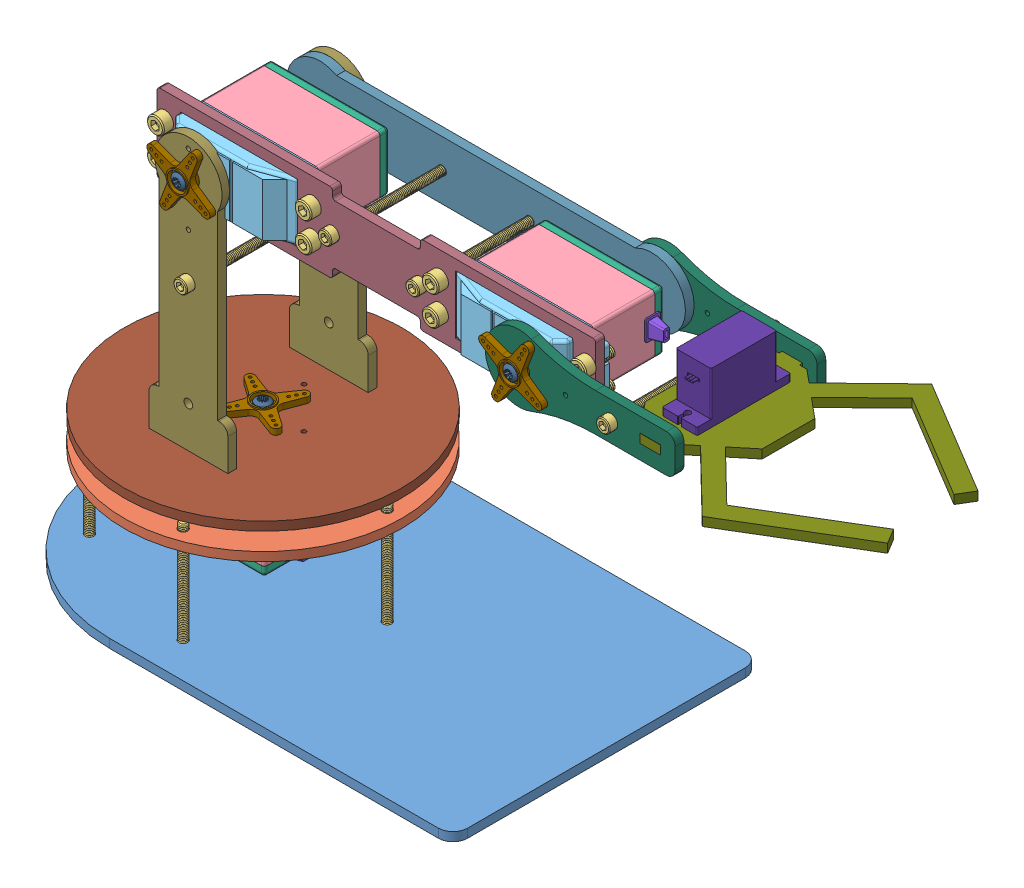
SolidWorks assembly robot_esamble_links, configuration Predeterminado. Lengths in mm.
Overall size (282.35 247.5 137.24).
60 component instances, 17 part files, 12 mates.
Components (placement in the parent):
- base_link_littleRobot-1: base_link_littleRobot [Predeterminado] at origin size (170 50.72 105)
  - A_pieza_arm_robot_v0-1: A_pieza_arm_robot_v0 [Predeterminado] x (0 0 -1) z (0 1 0) size (105 170 3)
  - B_pieza_arm_robot_v0-1: B_pieza_arm_robot_v0 [Predeterminado] at (0 33 0) x (-1 0 0) z (0 1 0) size (95 95 3)
  - socket head cap screw_ai-1: socket head cap screw_ai [HX-SHCS 0.112-48x1.5x1.5-S] at (13.1332 -2.8448 -40.4199) x (0 1 0) z (0 0 1) size (40.94 4.65 4.65)
  - socket head cap screw_ai-2: socket head cap screw_ai [HX-SHCS 0.112-48x1.5x1.5-S] at (-34.3832 -2.8448 -24.9809) x (0 1 0) z (0 0 1) size (40.94 4.65 4.65)
  - socket head cap screw_ai-3: socket head cap screw_ai [HX-SHCS 0.112-48x1.5x1.5-S] at (-34.3832 -2.8448 24.9809) x (0 1 0) z (0 0 1) size (40.94 4.65 4.65)
  - socket head cap screw_ai-4: socket head cap screw_ai [HX-SHCS 0.112-48x1.5x1.5-S] at (13.1332 -2.8448 40.4199) x (0 1 0) z (0 0 1) size (40.94 4.65 4.65)
  - socket head cap screw_ai-5: socket head cap screw_ai [HX-SHCS 0.112-48x1.5x1.5-S] at (42.5 -2.8448 0) x (0 1 0) z (0 0 1) size (40.94 4.65 4.65)
  - Servomoteur Futuba S3003-4: Servomoteur Futuba S3003 [Défaut] at (-9.3643 24.2642 -40.4) size (55.5 42.98 32.41)
    - Boitier-1: Boitier [Défaut] at (8.3252 -16.2642 40.4) size (40.4 21 20)
    - Couvercle supérieure-1: Couvercle supérieure [Défaut] at (9.3643 6.7358 40.4) size (55.5 13 20)
    - Couvercle inférieure-1: Couvercle inférieure [Défaut] at (4.9957 -19.3642 40.4) size (40.4 3.1 20)
    - Axe-1: Axe [Défaut] at (9.3643 15.2358 40.4) size (5 16 5)
    - Passe fil-1: Passe fil [Défaut] at (17.8143 -15.2642 40.4) x (0 0 -1) z (1 0 0) size (7 5 7.5)
    - Palonnier-1: Palonnier [Défaut] at (9.3643 21.7358 40.4) x (0.465117 0 -0.885249) z (0 1 0) size (24 24 5)
    - Vis CBL Z, M 2.5 - 5-1: Vis CBL Z, M 2.5 - 5 [Défaut] at (9.3643 21.7358 40.4) x (0.991239 0 0.132079) z (0 1 0) size (5 5 6.88)
  - socket head cap screw_ai-22: socket head cap screw_ai [HX-SHCS 0.138-40x0.3125x0.3125-S] at (15.5 39.5052 5) x (0 -1 0) z (0 0 1) size (11.44 5.74 5.74)
  - socket head cap screw_ai-23: socket head cap screw_ai [HX-SHCS 0.138-40x0.3125x0.3125-S] at (15.5 39.5052 -5) x (0 -1 0) z (0 0 1) size (11.44 5.74 5.74)
  - socket head cap screw_ai-24: socket head cap screw_ai [HX-SHCS 0.138-40x0.3125x0.3125-S] at (-35 39.5052 5) x (0 -1 0) z (0 0 1) size (11.44 5.74 5.74)
  - socket head cap screw_ai-25: socket head cap screw_ai [HX-SHCS 0.138-40x0.3125x0.3125-S] at (-35 39.5052 -5) x (0 -1 0) z (0 0 1) size (11.44 5.74 5.74)
- link_1_littleRobot-1: link_1_littleRobot [Predeterminado] at (0 42 0) size (95 96 95)
  - H_pieza_arm_robot_v0-1: H_pieza_arm_robot_v0 [Predeterminado] x (0 0 -1) z (0 1 0) size (95 95 3)
  - D_pieza_arm_robot_v0-1: D_pieza_arm_robot_v0 [piexa_motor_leva] at (0 84.5 25.5) x (-1 0 0) z (0 0 -1) size (27 96 3)
  - D_pieza_arm_robot_v0-2: D_pieza_arm_robot_v0 [Predeterminado] at (0 84.5 -22.5) x (-1 0 0) z (0 0 -1) size (27 96 3)
  - socket head cap screw_ai-6: socket head cap screw_ai [HX-SHCS 0.112-48x2.25x2.25-S] at (0 53 28.3448) x (0 0 -1) z (1 0 0) size (59.99 4.65 4.65)
- link_2_littleRobot-1: link_2_littleRobot [Predeterminado] at (-18.25 113 17.932) size (150.24 126.5 50.43)
  - C_pieza_arm_robot_v0-1: C_pieza_arm_robot_v0 [Predeterminado] at (75 13.5 -3) x (-1 0 0) z (0 0 1) size (150 27 3)
  - Servomoteur Futuba S3003-2: Servomoteur Futuba S3003 [Défaut] at (122.3857 53.9 -11.7358) x (1 0 0) z (0 -1 0) size (55.5 42.98 32.41)
    - Boitier-1: Boitier [Défaut] at (8.3252 -16.2642 40.4) size (40.4 21 20)
    - Couvercle supérieure-1: Couvercle supérieure [Défaut] at (9.3643 6.7358 40.4) size (55.5 13 20)
    - Couvercle inférieure-1: Couvercle inférieure [Défaut] at (4.9957 -19.3642 40.4) size (40.4 3.1 20)
    - Axe-1: Axe [Défaut] at (9.3643 15.2358 40.4) size (5 16 5)
    - Passe fil-1: Passe fil [Défaut] at (17.8143 -15.2642 40.4) x (0 0 -1) z (1 0 0) size (7 5 7.5)
    - Palonnier-1: Palonnier [Défaut] at (9.3643 21.7358 40.4) x (0.465117 0 -0.885249) z (0 1 0) size (24 24 5)
    - Vis CBL Z, M 2.5 - 5-1: Vis CBL Z, M 2.5 - 5 [Défaut] at (9.3643 21.7358 40.4) x (0.991239 0 0.132079) z (0 1 0) size (5 5 6.88)
  - Servomoteur Futuba S3003-3: Servomoteur Futuba S3003 [Défaut] at (27.6143 -26.9 -11.7358) x (-1 0 0) z (0 1 0) size (55.5 42.98 32.41)
    - Boitier-1: Boitier [Défaut] at (8.3252 -16.2642 40.4) size (40.4 21 20)
    - Couvercle supérieure-1: Couvercle supérieure [Défaut] at (9.3643 6.7358 40.4) size (55.5 13 20)
    - Couvercle inférieure-1: Couvercle inférieure [Défaut] at (4.9957 -19.3642 40.4) size (40.4 3.1 20)
    - Axe-1: Axe [Défaut] at (9.3643 15.2358 40.4) size (5 16 5)
    - Passe fil-1: Passe fil [Défaut] at (17.8143 -15.2642 40.4) x (0 0 -1) z (1 0 0) size (7 5 7.5)
    - Palonnier-1: Palonnier [Défaut] at (9.3643 21.7358 40.4) x (0.465117 0 -0.885249) z (0 1 0) size (24 24 5)
    - Vis CBL Z, M 2.5 - 5-1: Vis CBL Z, M 2.5 - 5 [Défaut] at (9.3643 21.7358 40.4) x (0.991239 0 0.132079) z (0 1 0) size (5 5 6.88)
  - E_pieza_arm_robot_v0-1: E_pieza_arm_robot_v0 [Predeterminado] at (75 13.5 -40.432) x (0 -1 0) z (0 0 1) size (23 136.5 3)
  - socket head cap screw_ai-11: socket head cap screw_ai [HX-SHCS 0.112-48x1.5x1.5-S] at (60 13.5 2.8448) x (0 0 -1) z (1 0 0) size (40.94 4.65 4.65)
  - socket head cap screw_ai-12: socket head cap screw_ai [HX-SHCS 0.112-48x1.5x1.5-S] at (90 13.5 2.8448) x (0 0 -1) z (1 0 0) size (40.94 4.65 4.65)
  - socket head cap screw_ai-14: socket head cap screw_ai [HX-SHCS 0.138-40x0.3125x0.3125-S] at (53.25 18.5 3.5052) x (0 0 -1) z (1 0 0) size (11.44 5.74 5.74)
  - socket head cap screw_ai-15: socket head cap screw_ai [HX-SHCS 0.138-40x0.3125x0.3125-S] at (53.25 8.5 3.5052) x (0 0 -1) z (1 0 0) size (11.44 5.74 5.74)
  - socket head cap screw_ai-16: socket head cap screw_ai [HX-SHCS 0.138-40x0.3125x0.3125-S] at (2.75 18.5 3.5052) x (0 0 -1) z (1 0 0) size (11.44 5.74 5.74)
  - socket head cap screw_ai-17: socket head cap screw_ai [HX-SHCS 0.138-40x0.3125x0.3125-S] at (2.75 8.5 3.5052) x (0 0 -1) z (1 0 0) size (11.44 5.74 5.74)
  - socket head cap screw_ai-18: socket head cap screw_ai [HX-SHCS 0.138-40x0.3125x0.3125-S] at (96.75 18.5 3.5052) x (0 0 -1) z (1 0 0) size (11.44 5.74 5.74)
  - socket head cap screw_ai-19: socket head cap screw_ai [HX-SHCS 0.138-40x0.3125x0.3125-S] at (96.75 8.5 3.5052) x (0 0 -1) z (1 0 0) size (11.44 5.74 5.74)
  - socket head cap screw_ai-20: socket head cap screw_ai [HX-SHCS 0.138-40x0.3125x0.3125-S] at (147.25 18.5 3.5052) x (0 0 -1) z (1 0 0) size (11.44 5.74 5.74)
  - socket head cap screw_ai-21: socket head cap screw_ai [HX-SHCS 0.138-40x0.3125x0.3125-S] at (147.25 8.5 3.5052) x (0 0 -1) z (1 0 0) size (11.44 5.74 5.74)
- link_3_littleRobot-1: link_3_littleRobot [Predeterminado] at origin size (127.85 30.45 78.46)
  - F_pieza_arm_robot_v0-1: F_pieza_arm_robot_v0 [Predeterminado] at (113.5 126.5 26) x (0 -1 0) z (0 0 -1) size (23 65 3)
  - F_pieza_arm_robot_v0-2: F_pieza_arm_robot_v0 [Predeterminado] at (113.5 126.5 -22.5) x (0 -1 0) z (0 0 -1) size (23 65 3)
  - G_pieza_arm_robot_v0-1: G_pieza_arm_robot_v0 [Predeterminado] at (158.5 124.95 0.75) x (0 0 1) z (0 1 0) size (78.46 83.35 3)
  - socket head cap screw_ai-13: socket head cap screw_ai [HX-SHCS 0.112-48x2.25x2.25-S] at (145 126.5 28.8448) x (0 0 -1) z (1 0 0) size (59.99 4.65 4.65)
  - Towerpro Micro Servo 9g-1: Towerpro Micro Servo 9g [Varsayılan] at (159.5 145.45 1) x (1 0 0) z (0 0 -1) size (12 30 32)
Mates (geometry in assembly coordinates):
- Coincidente1: coincident aligned: plane of base_link_littleRobot-1 through (0 0 0) normal (0 0 1)
- Coincidente2: coincident aligned: plane of base_link_littleRobot-1 through (0 0 0) normal (1 0 0)
- Coincidente3: coincident anti-aligned: plane of base_link_littleRobot-1/A_pieza_arm_robot_v0-1 through (0 0 0) normal (0 -1 0)
- Concéntrica1: concentric anti-aligned: cylinder of base_link_littleRobot-1/Servomoteur Futuba S3003-4/Axe-1 through (0 29.5 0) axis (0 1 0) radius 2.5; cylinder of link_1_littleRobot-1/H_pieza_arm_robot_v0-1 through (0 45 0) axis (0 -1 0) radius 2.5
- Coincidente4: coincident anti-aligned: plane of base_link_littleRobot-1/Servomoteur Futuba S3003-4/Couvercle supérieure-1 through (-4.75 42 0) normal (0 1 0); plane of link_1_littleRobot-1/H_pieza_arm_robot_v0-1 through (0 42 0) normal (0 -1 0)
- Concéntrica2: concentric anti-aligned: cylinder of link_1_littleRobot-1/D_pieza_arm_robot_v0-1 through (0 126.5 25.5) axis (0 0 -1) radius 2.5; cylinder of link_2_littleRobot-1/Servomoteur Futuba S3003-3/Axe-1 through (0 126.5 11.432) axis (0 0 1) radius 2.5
- Coincidente5: coincident anti-aligned: plane of link_1_littleRobot-1/D_pieza_arm_robot_v0-2 through (0 126.5 -22.5) normal (0 0 1); plane of link_2_littleRobot-1/E_pieza_arm_robot_v0-1 through (56.75 126.5 -22.5) normal (0 0 -1)
- Concéntrica3: concentric anti-aligned: cylinder of link_2_littleRobot-1/E_pieza_arm_robot_v0-1 through (113.5 126.5 -22.5) axis (0 0 1) radius 1.5; cylinder of link_3_littleRobot-1/F_pieza_arm_robot_v0-2 through (113.5 126.5 -22.5) axis (0 0 -1) radius 2.5
- Coincidente6: coincident anti-aligned: plane of link_2_littleRobot-1/E_pieza_arm_robot_v0-1 through (56.75 126.5 -22.5) normal (0 0 -1); plane of link_3_littleRobot-1/F_pieza_arm_robot_v0-2 through (113.5 126.5 -22.5) normal (0 0 1)
- Paralelo3: parallel aligned: plane of base_link_littleRobot-1/A_pieza_arm_robot_v0-1 through (0 3 52.5) normal (0 0 1); plane of link_1_littleRobot-1/D_pieza_arm_robot_v0-1 through (0 126.5 25.5) normal (0 0 1)
- Paralelo4: parallel anti-aligned: plane of base_link_littleRobot-1/A_pieza_arm_robot_v0-1 through (0 3 0) normal (0 1 0); plane of link_2_littleRobot-1/C_pieza_arm_robot_v0-1 through (-18.25 113 17.932) normal (0 -1 0)
- Paralelo5: parallel anti-aligned: plane of base_link_littleRobot-1/A_pieza_arm_robot_v0-1 through (0 3 0) normal (0 1 0); plane of link_3_littleRobot-1/F_pieza_arm_robot_v0-1 through (113.5 120 23) normal (0 -1 0)
